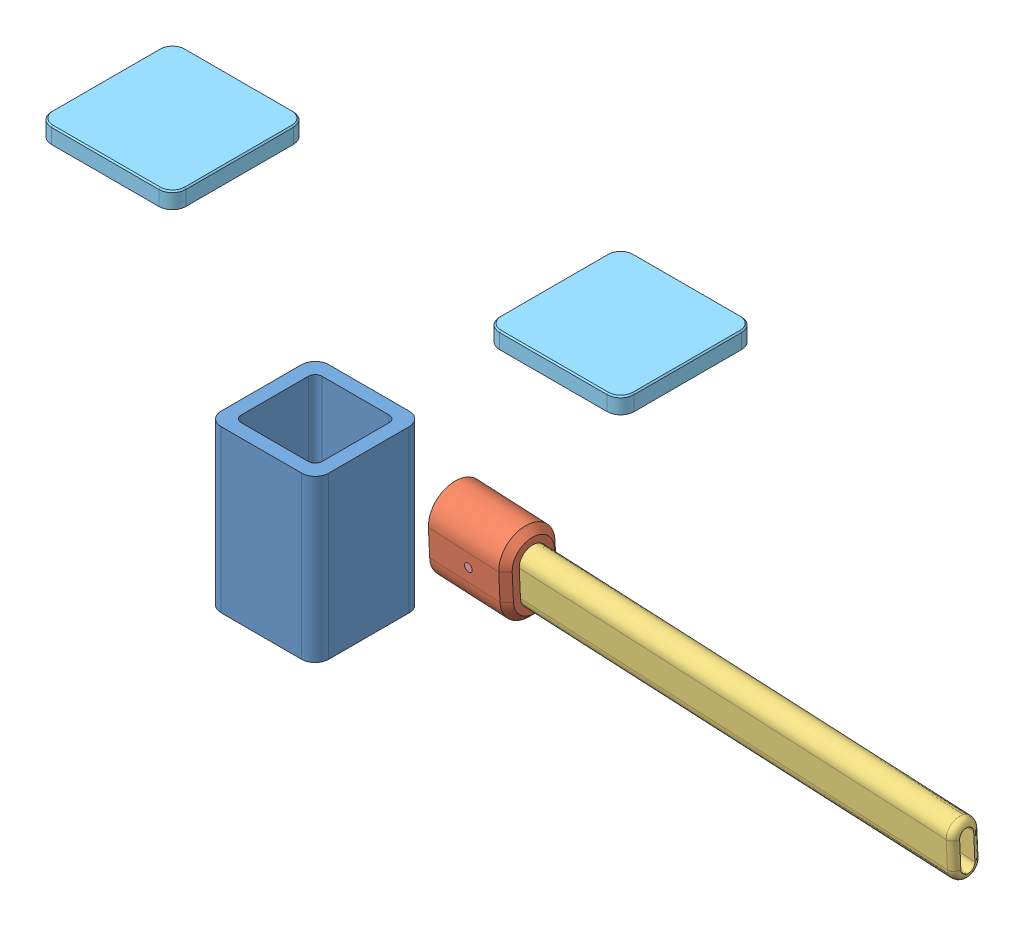
SolidWorks assembly Assem1, configuration Default. Lengths in mm.
Overall size (754.55 144 385.24).
6 component instances, 5 part files, 7 mates.
Components (placement in the parent):
- Part2-1: Part2 [Default] at (7.1889 56.5545 116.0759) size (80 120 80)
- Part3-2: Part3 [Default] at (108.0327 15.2868 80.4347) x (0.001059 -0.998986 -0.045005) z (-0.046996 -0.045005 0.997881) size (60 60 40)
- Part4-1: Part4 [Default] at (276.5379 70.0524 90.8405) x (-0.001059 0.998986 0.045005) z (0.046996 0.045005 -0.997881) size (40 400 20)
- Part5-1: Part5 [Default] at (108.7289 65.2353 82.7202) x (0.998895 -0.001059 0.046996) z (0.001059 -0.998986 -0.045005) size (6 40 6)
- Part1-2: Part1 [Default] at (-227.7364 122.5545 -12.6302) size (100 12 100)
- Part1-3: Part1 [Default] at (-60.779 -9.4455 -179.1618) size (100 12 100)
Mates (geometry in assembly coordinates):
- Coincident2: coincident anti-aligned: cylinder of Part3-2 through (109.6689 66.1354 62.7626) axis (-0.046996 -0.045005 0.997881) radius 3; circle of Part4-1
- Tangent1: tangent aligned: plane of Part5-1 through (107.789 64.3352 102.6778) normal (-0.046996 -0.045005 0.997881); circle of Part3-2
- Concentric1: concentric anti-aligned: cylinder of Part3-2 through (109.6689 66.1354 62.7626) axis (-0.046996 -0.045005 0.997881) radius 3; cylinder of Part5-1 through (107.789 64.3352 102.6778) axis (0.046996 0.045005 -0.997881) radius 3
- Coincident4: coincident anti-aligned: plane of Part2-1 through (37.1889 -3.4455 146.0759) normal (0 -1 0); plane of Part1-3 through (-100.779 -3.4455 -139.1618) normal (0 1 0)
- Parallel1: parallel aligned: plane of Part3-2 through (78.0023 75.2578 81.7252) normal (-0.998895 0.001059 -0.046996); plane of Part4-1 through (76.7749 55.2794 80.7663) normal (-0.998895 0.001059 -0.046996)
- Coincident11: coincident anti-aligned: plane of Part3-2 through (137.4661 74.7442 94.5237) normal (0.046996 0.045005 -0.997881); plane of Part4-1 through (475.8628 54.4058 109.5434) normal (-0.046996 -0.045005 0.997881)
- Coincident13: coincident anti-aligned: plane of Part2-1 through (37.1889 116.5545 146.0759) normal (0 1 0); plane of Part1-2 through (-267.7364 116.5545 27.3698) normal (0 -1 0)
